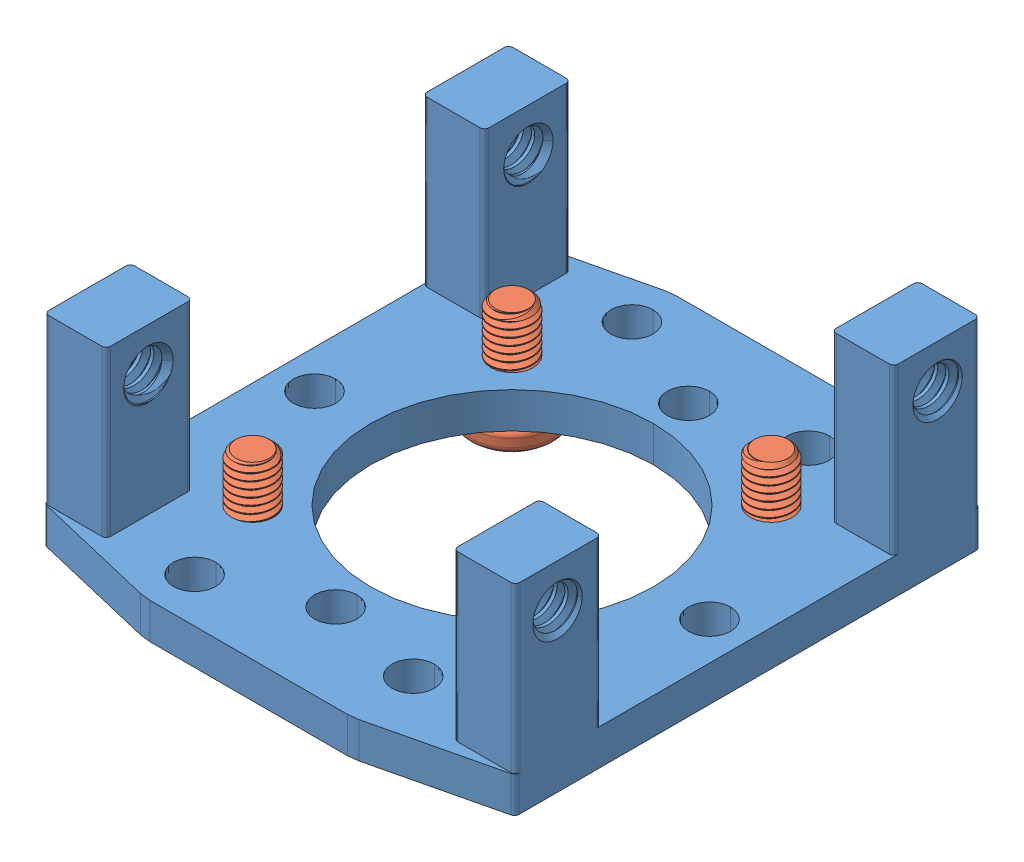
SolidWorks assembly 555188 assembly.STEP, configuration Default. Lengths in mm.
Overall size (33.4 16.56 37.36).
5 component instances, 2 part files, 0 mates.
Components (placement in the parent):
- 555188.STEP-1: 555188.STEP [Default] at (-6.4793 1.7739 -2.6152) size (33.4 14.22 37.36)
- 555188 screw_92005A116.STEP-1: 555188 screw_92005A116.STEP [Default] at (-15.6717 7.7739 6.5772) x (1 0 0) z (0 -1 0) size (6 6 8.35)
- 555188 screw_92005A116.STEP-2: 555188 screw_92005A116.STEP [Default] at (2.7131 7.7739 6.5772) x (0 0 -1) z (0 -1 0) size (6 6 8.35)
- 555188 screw_92005A116.STEP-3: 555188 screw_92005A116.STEP [Default] at (2.7131 7.7739 -11.8076) x (-1 0 0) z (0 -1 0) size (6 6 8.35)
- 555188 screw_92005A116.STEP-4: 555188 screw_92005A116.STEP [Default] at (-15.6717 7.7739 -11.8076) x (0 0 1) z (0 -1 0) size (6 6 8.35)
